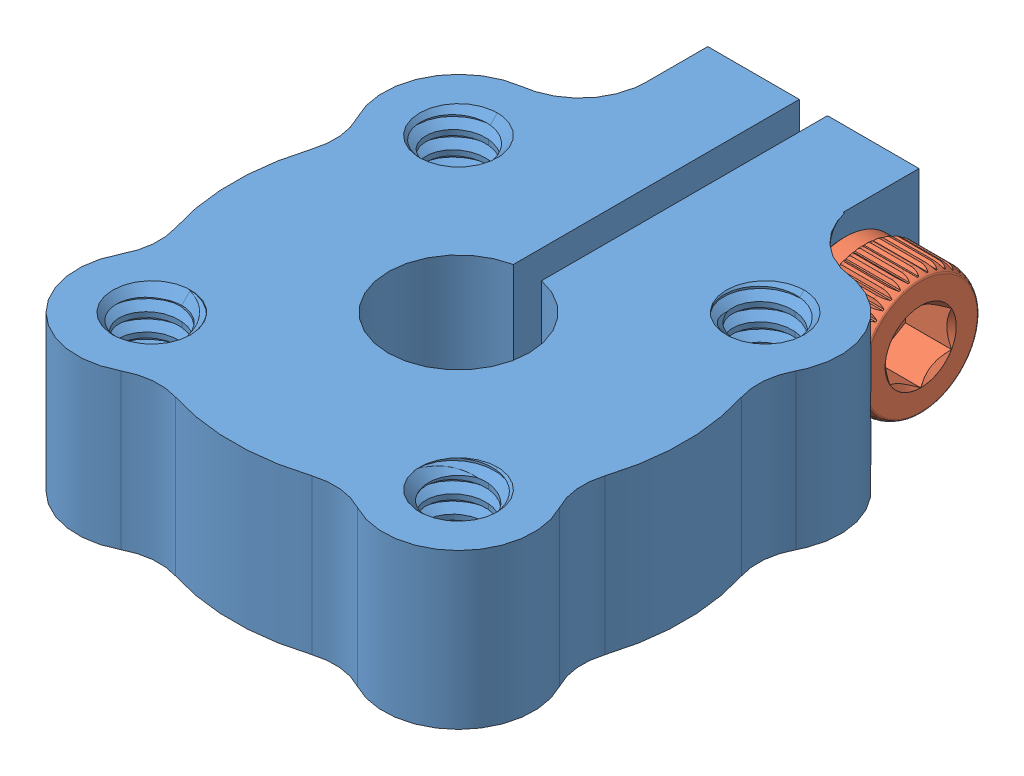
SolidWorks assembly 545588 assembly, configuration Default. Lengths in mm.
Overall size (100.53 31.16 84.78).
3 component instances, 2 part files, 0 mates.
Components (placement in the parent):
- 545588 assembly.STEP-1: 545588 assembly.STEP [Default] at origin size (100.53 31.16 84.78)
  - 545588.STEP-1: 545588.STEP [Default] at (-87.4372 18.8221 32.8798) size (20.57 9.53 26.29)
  - 632110_90128A121.STEP-1: 632110_90128A121.STEP [Default] at (-120.7747 24.8546 20.3068) x (0 0 1) z (-1 0 0) size (5.61 5.61 13.03)
